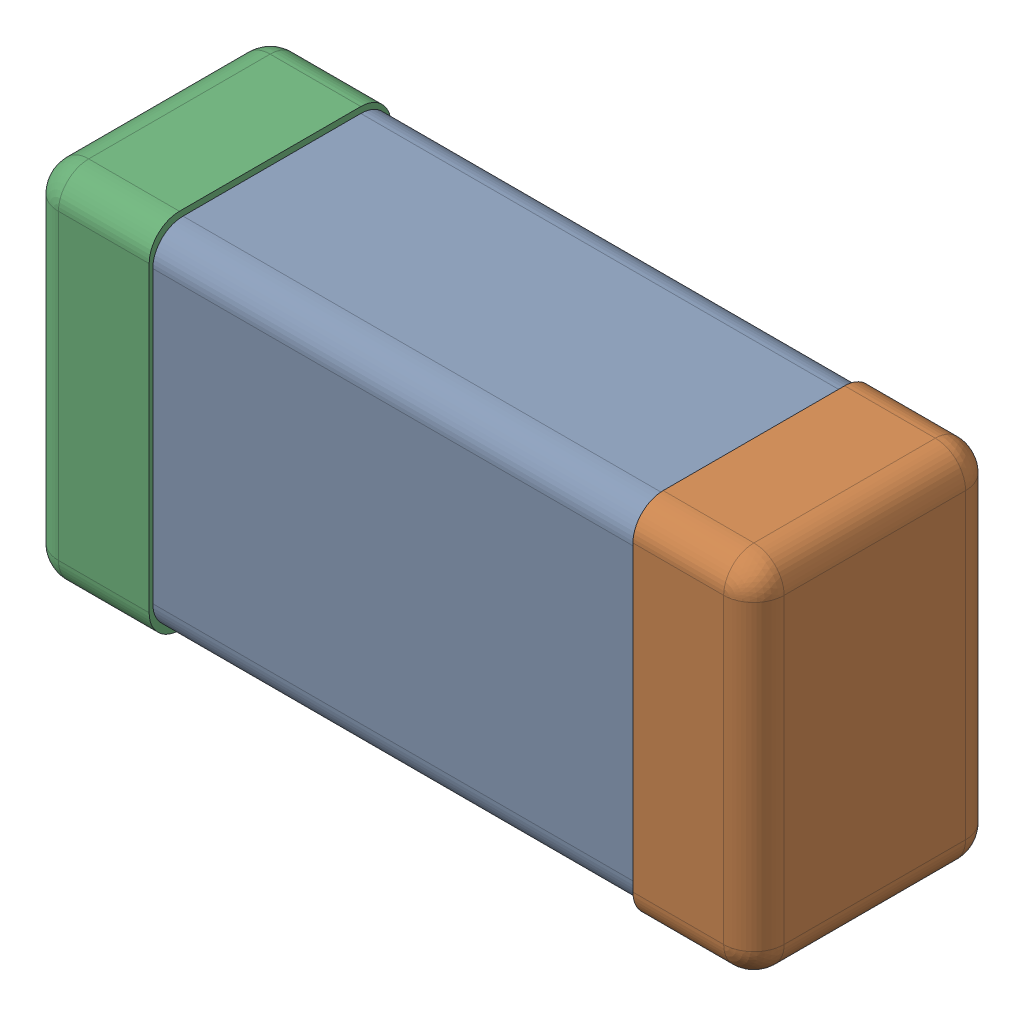
SolidWorks assembly C0201_020_18, configuration Standard. Lengths in mm.
Overall size (0.6 0.3 0.2).
4 component instances, 3 part files, 0 mates.
Components (placement in the parent):
- C0201_020_19-1: C0201_020_19 [Standard] at origin size (0.6 0.3 0.2)
  - Part 3_2-1: Part 3_2 [Standard] at (0 0 -7.3015) size (0.5 0.29 0.2)
  - Part 2_2-1: Part 2_2 [Standard] at (0 0 -7.3) size (0.1 0.3 0.2)
  - Part 1_2-1: Part 1_2 [Standard] at (0 0 -7.3) size (0.1 0.3 0.2)
